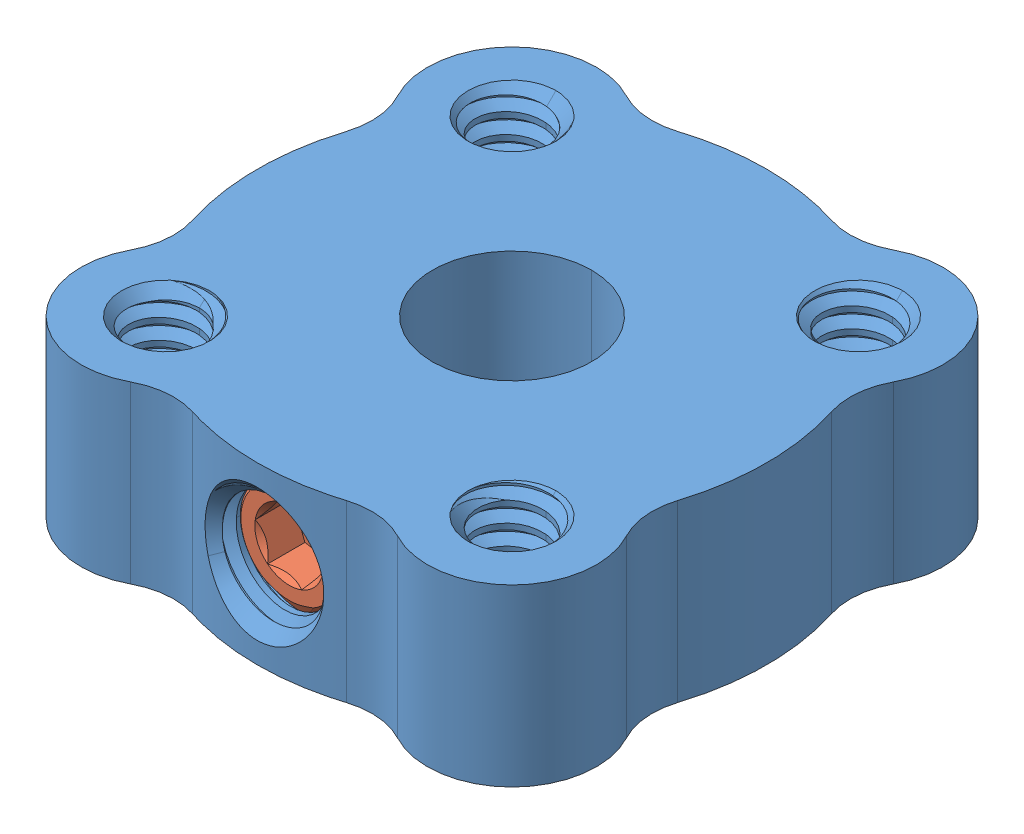
SolidWorks assembly 545548_hub, configuration Default. Lengths in mm.
Overall size (20.57 9.53 20.57).
3 component instances, 2 part files, 0 mates.
Components (placement in the parent):
- 545548 assembly.STEP-1: 545548 assembly.STEP [Default] at origin size (20.57 9.53 20.57)
  - 545548.STEP-1: 545548.STEP [Default] at (-38.9112 12.0765 8.9709) size (20.57 9.53 20.57)
  - 632138_91375A438.STEP-1: 632138_91375A438.STEP [Default] at (-38.9112 18.109 15.0823) x (0.93363 0.358238 0) z (0 0 1) size (4.83 4.83 6.36)
